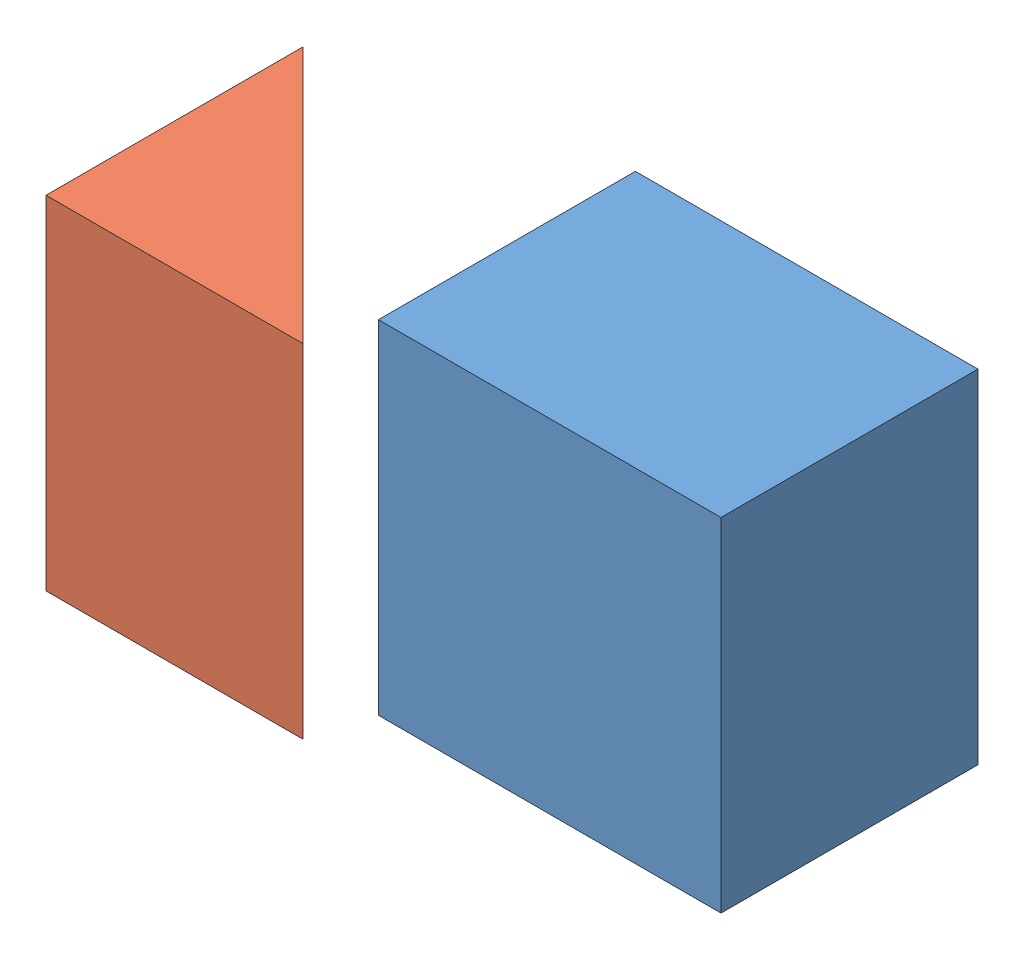
SolidWorks assembly Assembly 58 (Fix part & Float part), configuration Default. Lengths in mm.
Overall size (47.54 27.23 21.55).
2 component instances, 2 part files, 0 mates.
Components (placement in the parent):
- rectangle_1_2013-1: rectangle_1_2013 [Default] at (-0.6431 -0.9026 28.6528) size (25.4 25.4 19.05)
- Traingle_2013-1: Traingle_2013 [Default] at (-22.7842 -2.7356 31.1518) size (19.05 25.4 19.05)
